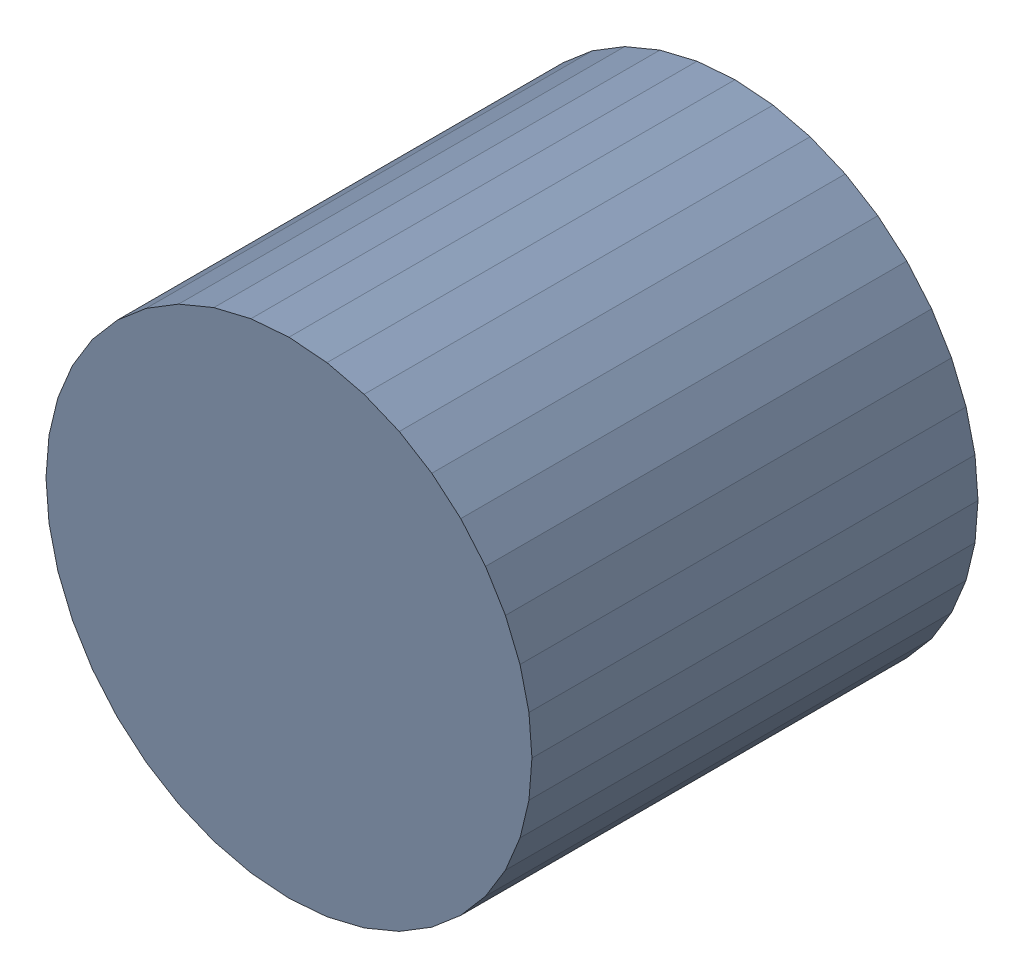
SolidWorks assembly C10_Motor_6Kanaloa_v2.0.0_Motor, configuration Default. Lengths in mm.
Overall size (6.32 6.32 5.8).
2 component instances, 1 part files, 0 mates.
Components (placement in the parent):
- 352892112-1: 352892112 [Default] at (46.17 127 0) size (6.32 6.32 5.8)
  - Extruded_11-1: Extruded_11 [Default] at origin size (6.32 6.32 5.8)
